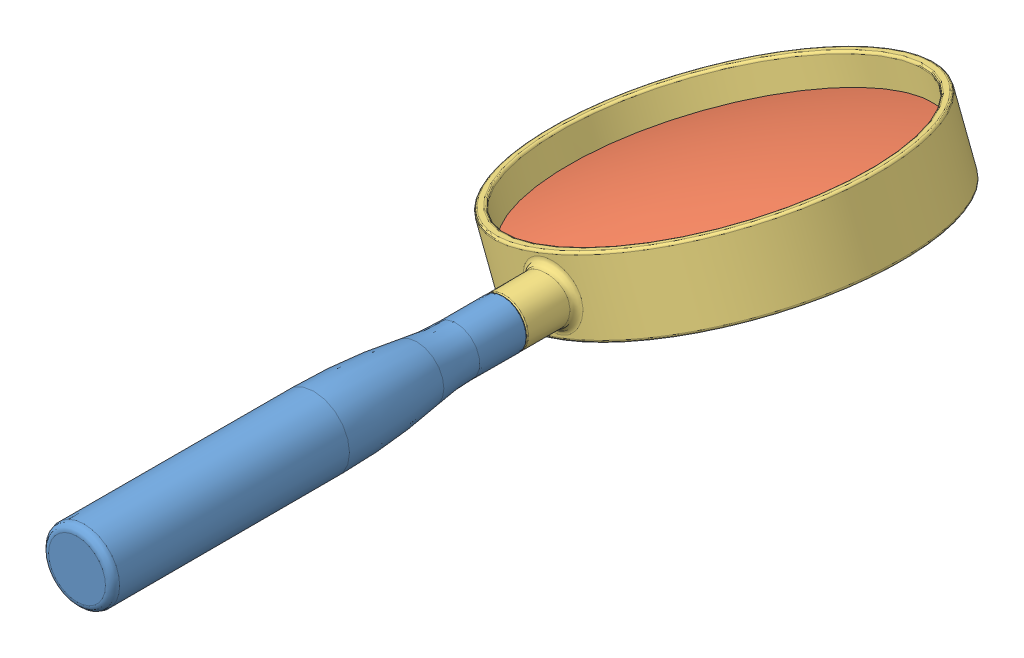
SolidWorks assembly MagnifyingGlassAssembly-notdone, configuration Default. Lengths in mm.
Overall size (74.44 40.62 174).
3 component instances, 3 part files, 4 mates.
Components (placement in the parent):
- Handle-1: Handle [Default] at (38.0724 41.8474 43.3889) size (15 15 100)
- Lens-1: Lens [Default] at (38.0724 41.8474 -3.6111) x (0.933026 0.359809 0) z (0 0 1) size (70 10 70)
- Ring-1: Ring [Default] at (38.0724 41.8474 -3.6111) x (0.933026 0.359809 0) z (0 0 1) size (74 15 84)
Mates (geometry in assembly coordinates):
- Coincident1: coincident: plane of Handle-1 through (38.0724 44.8474 43.3889) normal (0 0 -1); plane of Ring-1 through (38.0724 41.8474 43.3889) normal (0 0 1)
- Concentric2: concentric: cylinder of Handle-1 through (38.0724 41.8474 -78.0283) axis (0 0 -1) radius 3; cylinder of Ring-1 through (38.0724 41.8474 33.3889) axis (0 0 1) radius 3
- Distance1: distance = 0 mm: cylinder of Lens-1 through (24.0862 78.1152 -3.6111) axis (-0.359809 0.933026 0) radius 35; cylinder of Ring-1 through (32.582 56.0845 -3.6111) axis (-0.359809 0.933026 0) radius 35
- Coincident2: coincident: axis of Handle-1 through (38.0724 41.8474 43.3889) axis (0 0 -1); line of Lens-1 through (38.0724 41.8474 -84.5111) axis (0 0 1)
